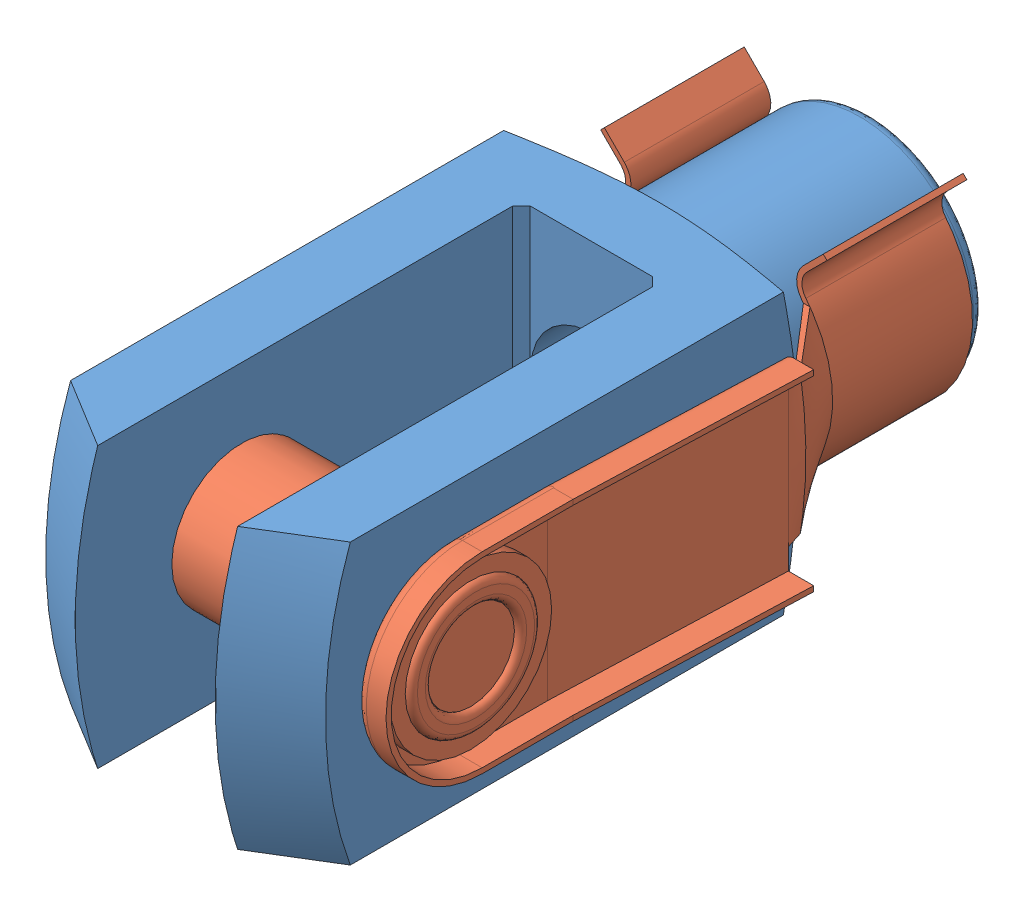
SolidWorks assembly 2676 SG-M16, configuration Default. Lengths in mm.
Overall size (40.43 32 83).
2 component instances, 2 part files, 0 mates.
Components (placement in the parent):
- 2676 SG-M16---(GK)-1: 2676 SG-M16---(GK) [Default] at (0 0 64) x (-1 0 0) z (0 0 1) size (32 32 83)
- 200285 FKB-16X32-1: 200285 FKB-16X32 [Default] at (0 0 18) x (0 1 0) z (0 0 -1) size (27.6 40.43 73)
